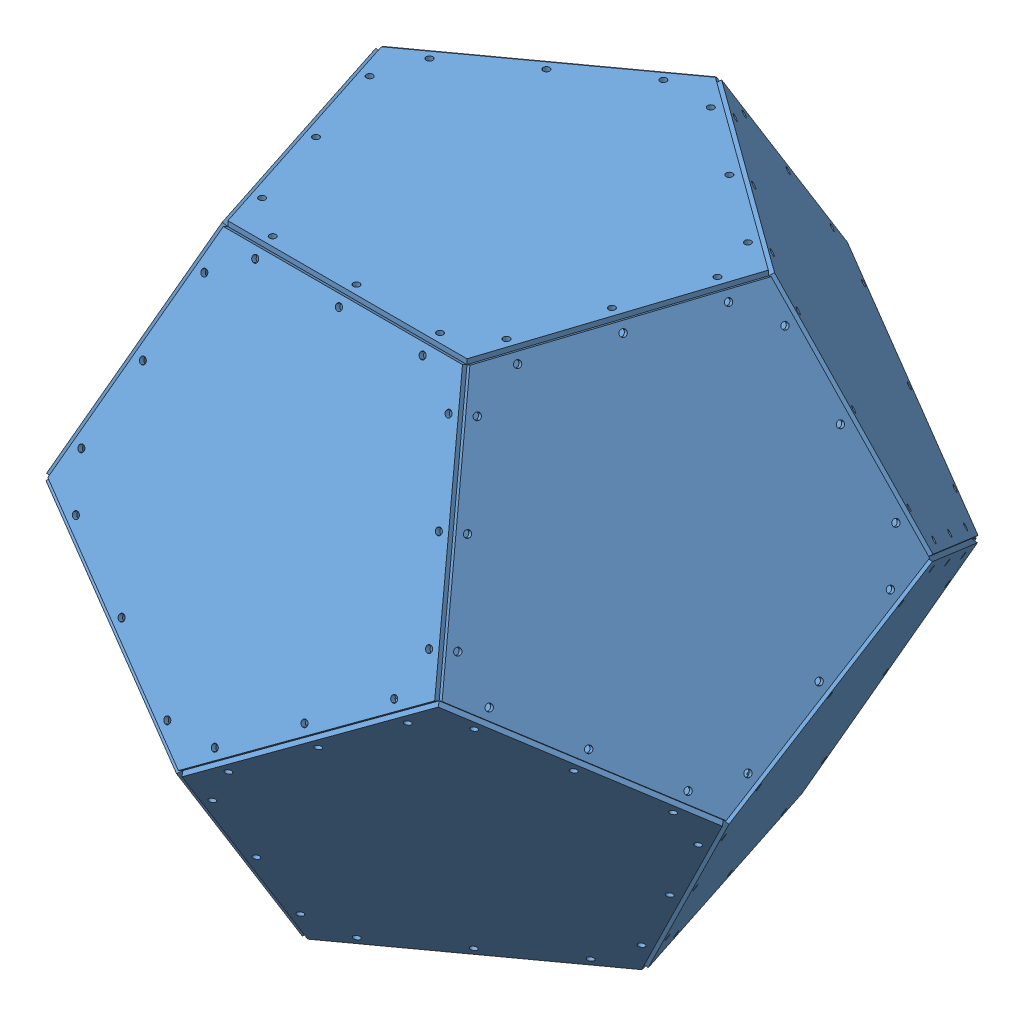
SolidWorks assembly Panels With No Gap, configuration Default. Lengths in mm.
Overall size (400.53 288.17 407.48).
12 component instances, 1 part files, 13 mates.
Components (placement in the parent):
- Acrylic Sid Plate-1: Acrylic Sid Plate [Default] at (0 -142.7501 0) x (1 0 0) z (0 0 -1) size (205.49 2.67 195.43)
- Acrylic Sid Plate-2: Acrylic Sid Plate [Default] at (0 142.7501 0) size (205.49 2.67 195.43)
- Acrylic Sid Plate-6: Acrylic Sid Plate [Default] at (-121.4305 -63.8398 -39.4552) x (0.309017 0 -0.951057) z (0.425325 -0.894427 0.138197) size (205.49 2.67 195.43)
- Acrylic Sid Plate-7: Acrylic Sid Plate [Default] at (-121.4305 63.8398 39.4552) x (-0.309017 0 -0.951057) z (0.425325 0.894427 -0.138197) size (205.49 2.67 195.43)
- Acrylic Sid Plate-8: Acrylic Sid Plate [Default] at (0 -63.8398 -127.6796) x (1 0 0) z (0 -0.894427 0.447214) size (205.49 2.67 195.43)
- Acrylic Sid Plate-9: Acrylic Sid Plate [Default] at (121.4305 -63.8398 -39.4552) x (0.309017 0 0.951057) z (-0.425325 -0.894427 0.138197) size (205.49 2.67 195.43)
- Acrylic Sid Plate-10: Acrylic Sid Plate [Default] at (75.0482 -63.8398 103.2949) x (-0.809017 0 0.587785) z (-0.262866 -0.894427 -0.361803) size (205.49 2.67 195.43)
- Acrylic Sid Plate-11: Acrylic Sid Plate [Default] at (-75.0482 -63.8398 103.2949) x (-0.809017 0 -0.587785) z (0.262866 -0.894427 -0.361803) size (205.49 2.67 195.43)
- Acrylic Sid Plate-12: Acrylic Sid Plate [Default] at (-75.0482 63.8398 -103.2949) x (0.809017 0 -0.587785) z (0.262866 0.894427 0.361803) size (205.49 2.67 195.43)
- Acrylic Sid Plate-13: Acrylic Sid Plate [Default] at (75.0482 63.8398 -103.2949) x (0.809017 0 0.587785) z (-0.262866 0.894427 0.361803) size (205.49 2.67 195.43)
- Acrylic Sid Plate-14: Acrylic Sid Plate [Default] at (121.4305 63.8398 39.4552) x (-0.309017 0 0.951057) z (-0.425325 0.894427 -0.138197) size (205.49 2.67 195.43)
- Acrylic Sid Plate-15: Acrylic Sid Plate [Default] at (0 63.8398 127.6796) x (-1 0 0) z (0 0.894427 -0.447214) size (205.49 2.67 195.43)
Mates (geometry in assembly coordinates):
- Coincident1: coincident: line of Acrylic Sid Plate-1 through (0 -179.1091 0) axis (0 1 0)
- Parallel1: parallel anti-aligned: plane of Acrylic Sid Plate-1 through (0 -142.7501 0) normal (0 -1 0)
- Coincident3: coincident anti-aligned: plane of Acrylic Sid Plate-1 through (0 -142.7501 0) normal (0 0 -1)
- Coincident4: coincident aligned: line of Acrylic Sid Plate-2 through (75.0812 0 179.1091) axis (0 0 -1)
- Coincident5: coincident aligned: plane of Acrylic Sid Plate-2 through (0 142.7501 0) normal (0 0 1)
- Symmetric1: symmetric aligned: plane of Acrylic Sid Plate-1 through (0 -141.4166 0) normal (0 1 0); plane of Acrylic Sid Plate-2 through (0 141.4166 0) normal (0 -1 0)
- Distance2: distance = 254 mm anti-aligned: plane of Acrylic Sid Plate-1 through (0 -127 0) normal (0 1 0); plane of Acrylic Sid Plate-2 through (0 127 0) normal (0 -1 0)
- Coincident12: coincident: plane of Acrylic Sid Plate-6 through (-121.4305 -63.8398 -39.4552) normal (0.309017 0 -0.951057)
- Coincident13: coincident aligned: line of Acrylic Sid Plate-1 through (-102.7452 -141.4166 33.3839) axis (0.309017 0 -0.951057); line of Acrylic Sid Plate-6 through (-102.7452 -141.4166 33.3839) axis (0.309017 0 -0.951057)
- Coincident14: coincident: plane of Acrylic Sid Plate-7 through (-121.4305 63.8398 39.4552) normal (-0.309017 0 -0.951057)
- Coincident15: coincident anti-aligned: line of Acrylic Sid Plate-2 through (-102.7452 129.667 -33.3839) axis (0.309017 0 0.951057); line of Acrylic Sid Plate-7 through (-63.5 129.667 87.4003) axis (-0.309017 0 -0.951057)
- Coincident16: coincident anti-aligned: line of Acrylic Sid Plate-2 through (-102.7452 141.4166 -33.3839) axis (0.309017 0 0.951057); line of Acrylic Sid Plate-7 through (-63.5 141.4166 87.4003) axis (-0.309017 0 -0.951057)
- Coincident19: coincident aligned: line of Acrylic Sid Plate-6 through (-166.2452 33.3839 -54.0163) axis (0 -0.525731 0.850651); line of Acrylic Sid Plate-7 through (-166.2452 33.3839 -54.0163) axis (0 -0.525731 0.850651)
